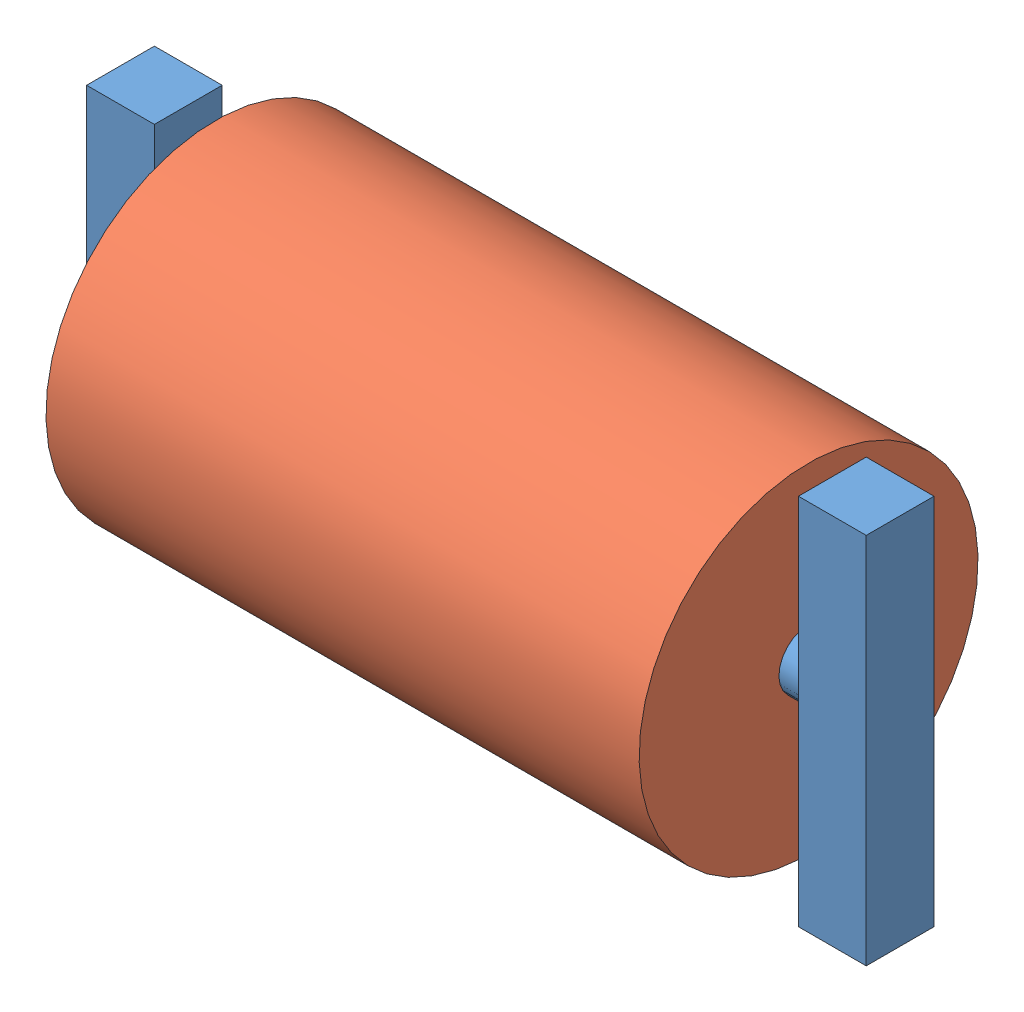
SolidWorks assembly Upper_roller, configuration Default. Lengths in mm.
Overall size (460 222.94 205.88).
2 component instances, 2 part files, 2 mates.
Components (placement in the parent):
- rail_mpver-1: rail_mpver [Default] at (-94.5545 253.0282 373.9621) size (460 220 40)
- Roller-1: Roller [Default] at (116.4455 263.0282 373.9621) x (0 -0.029844 0.999555) z (-1 0 0) size (200 200 350)
Mates (geometry in assembly coordinates):
- Concentric1: concentric: cylinder of rail_mpver-1 through (115.4455 263.0282 373.9621) axis (-1 0 0) radius 17.5; cylinder of Roller-1 through (-58.5545 263.0282 373.9621) axis (1 0 0) radius 17.5
- Distance1: distance = 16 mm anti-aligned: plane of Roller-1 through (-58.5545 263.0282 373.9621) normal (-1 0 0); plane of rail_mpver-1 through (-74.5545 363.0282 393.9621) normal (1 0 0)
